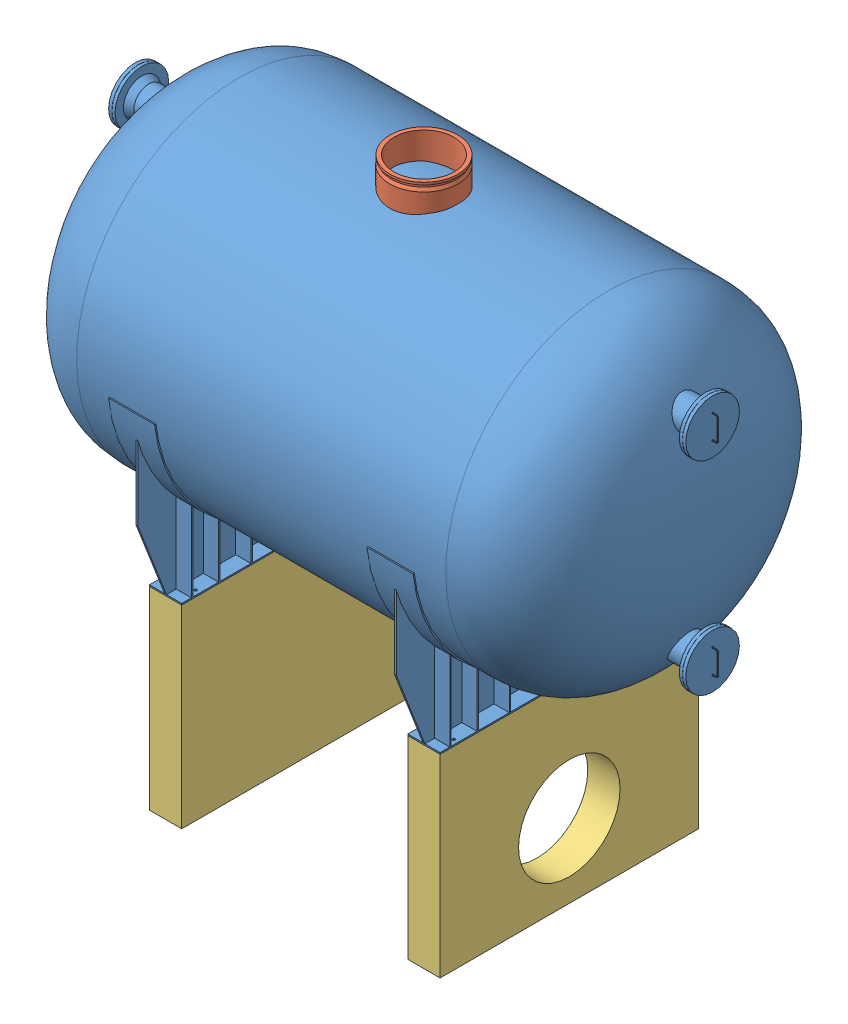
SolidWorks assembly Molekulsko sito, configuration Default. Lengths in mm.
Overall size (6378.51 6910.92 3536.51).
4 component instances, 3 part files, 4 mates.
Components (placement in the parent):
- Plast-2: Plast [Default] at origin size (6378.51 3864 3536.51)
- Prikljucak-1: Prikljucak [Default] at origin size (739.5 332.16 739.5)
- Prikljucak-2: Prikljucak [Default] x (1 0 0) z (0 0 -1) size (739.5 332.16 739.5)
- TEMELJI-1: TEMELJI [Default] at origin size (3150 2100 2800)
Mates (geometry in assembly coordinates):
- InPlace1: in place: plane of ? through (0 0 0) normal (0 0 1); moOrthogonalPlaneRef_w of ? through (0 0 0) normal (0 1 0); plane of ? through (0 0 0) normal (1 0 0); unknown of ?
- Coincident1: coincident aligned: plane of ?; plane of assembly
- Coincident2: coincident aligned: plane of ? through (0 0 0) normal (0 1 0)
- Coincident3: coincident anti-aligned: plane of ? through (0 0 0) normal (1 0 0); sketch_entity of ?
